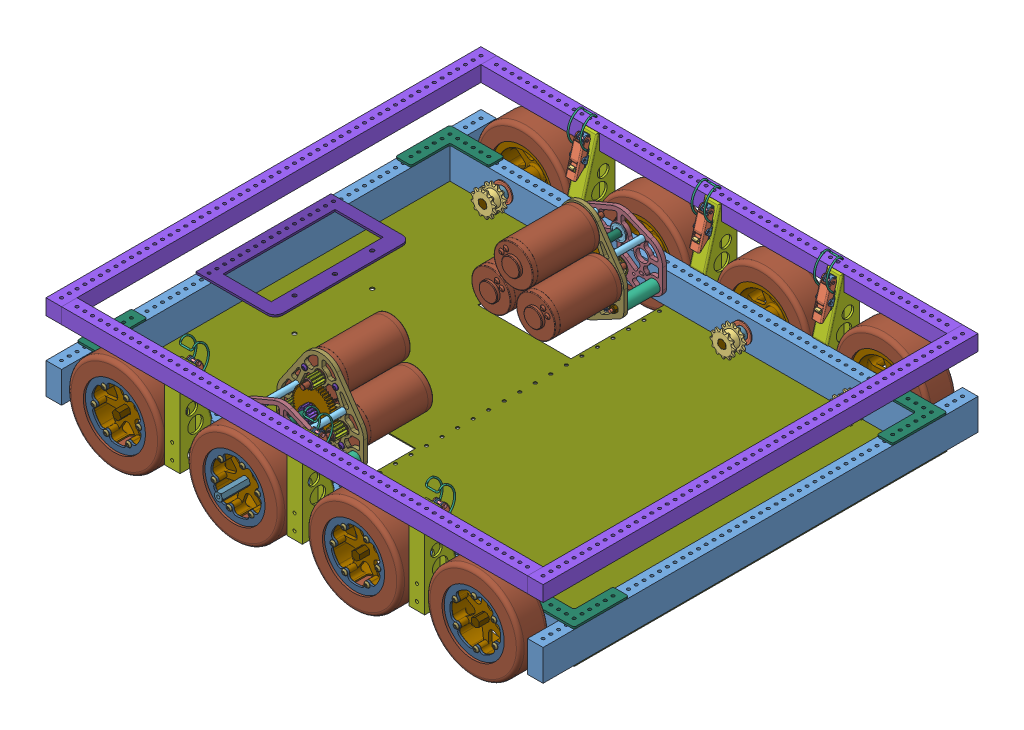
SolidWorks assembly 1991-17-DA-005, configuration Default. Lengths in mm.
Overall size (1080.45 259.05 1407.35).
273 component instances, 48 part files, 21 mates.
Components (placement in the parent):
- 1991-17-DA-001-1: 1991-17-DA-001 [Default] at (406.6265 809.065 1092.1988) size (1080.45 199.26 1407.35)
  - Master Frame Drivetrain-1: Master Frame Drivetrain [Default] at (262.4677 448.4138 629.0158) size (812.8 50.8 711.2)
  - 1991-17-DP-005-1: 1991-17-DP-005 [Default] at (-30.8765 451.5888 927.4658) x (-0.365997 0.930616 0) z (0.930616 0.365997 0) size (31.12 7.94 31.12)
  - 1991-17-DP-005-2: 1991-17-DP-005 [Default] at (164.6777 448.4138 927.4658) x (1 0 0) z (0 -1 0) size (31.12 7.94 31.12)
  - 1991-17-DP-005-3: 1991-17-DP-005 [Default] at (555.8119 451.5888 927.4658) x (0.865913 0.500195 0) z (0.500195 -0.865913 0) size (31.12 7.94 31.12)
  - 1991-17-DP-005-4: 1991-17-DP-005 [Default] at (360.2577 448.4138 927.4658) x (0.906341 -0.422547 0) z (-0.422547 -0.906341 0) size (31.12 7.94 31.12)
  - 1991-17-DP-005-5: 1991-17-DP-005 [Default] at (-30.8765 451.5888 914.7658) x (1 0 0) z (0 1 0) size (31.12 7.94 31.12)
  - 1991-17-DP-005-7: 1991-17-DP-005 [Default] at (360.2577 448.4138 914.7658) x (1 0 0) z (0 1 0) size (31.12 7.94 31.12)
  - 1991-17-DP-005-8: 1991-17-DP-005 [Default] at (555.8119 451.5888 914.7658) x (1 0 0) z (0 1 0) size (31.12 7.94 31.12)
  - 1991-17-DP-005-9: 1991-17-DP-005 [Default] at (555.8119 451.5888 343.2658) x (1 0 0) z (0 -1 0) size (31.12 7.94 31.12)
  - 1991-17-DP-005-10: 1991-17-DP-005 [Default] at (555.8119 451.5888 330.5658) x (1 0 0) z (0 1 0) size (31.12 7.94 31.12)
  - 1991-17-DP-005-11: 1991-17-DP-005 [Default] at (360.2577 448.4138 330.5658) x (1 0 0) z (0 1 0) size (31.12 7.94 31.12)
  - 1991-17-DP-005-12: 1991-17-DP-005 [Default] at (360.2577 448.4138 343.2658) x (1 0 0) z (0 -1 0) size (31.12 7.94 31.12)
  - 1991-17-DP-005-13: 1991-17-DP-005 [Default] at (164.6777 448.4138 343.2658) x (1 0 0) z (0 -1 0) size (31.12 7.94 31.12)
  - 1991-17-DP-005-15: 1991-17-DP-005 [Default] at (-30.8765 451.5888 330.5658) x (1 0 0) z (0 1 0) size (31.12 7.94 31.12)
  - 1991-17-DP-005-16: 1991-17-DP-005 [Default] at (-30.8765 451.5888 343.2658) x (1 0 0) z (0 -1 0) size (31.12 7.94 31.12)
  - 1991-17-DP-006-1: 1991-17-DP-006 [Default] at (-30.8765 451.5888 876.45) x (0.66365 -0.748043 0) z (0 0 1) size (40.29 40.29 21.35)
  - 1991-17-DP-006-2: 1991-17-DP-006 [Default] at (360.2577 448.4138 876.45) size (40.29 40.29 21.35)
  - 1991-17-DP-006-3: 1991-17-DP-006 [Default] at (555.8119 451.5888 876.45) size (40.29 40.29 21.35)
  - 1991-17-DP-006-4: 1991-17-DP-006 [Default] at (555.8119 451.5888 364.5255) x (0.485442 0.874269 0) z (0 0 1) size (40.29 40.29 21.35)
  - 1991-17-DP-006-5: 1991-17-DP-006 [Default] at (360.2577 448.4138 364.5255) x (0.316887 -0.948463 0) z (0 0 1) size (40.29 40.29 21.35)
  - 1991-17-DP-006-6: 1991-17-DP-006 [Default] at (-30.8765 451.5888 364.5255) size (40.29 40.29 21.35)
  - 1991-17-DA-002-1: 1991-17-DA-002 [Default] at (164.6777 495.4546 838.5658) size (142.06 172.49 287.64)
    - 217-2731-1: 217-2731 [Default] at (0 -47.0408 0) x (0.751182 -0.660095 0) z (-0.660095 -0.751182 0) size (31.12 7.94 31.12)
    - 217-2733-1: 217-2733 [Default] at (0 0 7.9375) x (0 0 -1) z (0.979051 -0.203616 0) size (7.11 24.61 24.61)
    - 217-2733-2: 217-2733 [Default] at (0 0 61.9125) x (0 0 1) z (-0.773016 -0.634387 0) size (7.11 24.61 24.61)
    - 217-2734-1: 217-2734 [Default] at (0 -47.0408 90.4875) x (1 0 0) z (0 -1 0) size (31.12 7.94 31.12)
    - 217-3099-001_12t-1: 217-3099-001_12t [Default] at (-36.6388 -14.5464 15.811) x (0.998588 0.053124 0) z (0 0 1) size (18.01 18.01 19.05)
    - 217-3099-001_12t-2: 217-3099-001_12t [Default] at (36.6388 -14.5464 15.811) x (0.998588 -0.053124 0) z (0 0 1) size (18.01 18.01 19.05)
    - 217-3099-001_12t-3: 217-3099-001_12t [Default] at (-0.0318 39.4208 15.811) x (-0.050001 -0.998749 0) z (0 0 1) size (18.01 18.01 19.05)
    - 217-3100-001_14t-1: 217-3100-001_14t [Default] at (0 0 26.9367) x (0.913978 0.405765 0) z (0 0 1) size (20.32 20.6 12.7)
    - 217-2711-002 Rev1_50t-1: 217-2711-002 Rev1_50t [Default] at (0 0 14.2621) x (-0.21459 -0.976704 0) z (0 0 1) size (66.7 66.76 12.65)
    - 217-2714-002 Rev1_60t-1: 217-2714-002 Rev1_60t [Default] at (0 -47.0408 26.9621) x (0.920953 -0.389675 0) z (0 0 1) size (78.95 78.95 12.65)
    - 217-2000-1: 217-2000 [Default] at (-36.6388 -14.5464 0) x (0 0 -1) z (0.998588 0.053124 0) size (150.2 64.01 64.01)
    - 217-2000-2: 217-2000 [Default] at (-0.0318 39.4208 0) x (0 0 -1) z (-0.050001 -0.998749 0) size (150.2 64.01 64.01)
    - 217-2000-3: 217-2000 [Default] at (36.6388 -14.5464 0) x (0 0 -1) z (0.998588 -0.053124 0) size (150.2 64.01 64.01)
    - 217-3421-001 Rev1-1: 217-3421-001 Rev1 [Default] at origin size (142.02 161.39 6.35)
    - 217-3421-002 Rev1-1: 217-3421-002 Rev1 [Default] at (0 0 69.85) x (-1 0 0) z (0 0 -1) size (142.06 121.97 6.35)
    - 217-3421-004 Rev1-1: 217-3421-004 Rev1 [Default] at (0 -47.0408 90.4875) x (-0.41446 0.910068 0) z (0 0 1) size (15.59 12.7 175.64)
    - 217-3422-001 Rev1-1: 217-3422-001 Rev1 [Default] at (0 0 34.925) x (0.99441 -0.105586 0) z (0 0 1) size (11.11 11.11 68.26)
    - 217-3422-004 Rev2-1: 217-3422-004 Rev2 [Default] at (0 -47.0408 96.8375) size (72.39 47.62 34.67)
    - 217-3421-009 Rev1-1: 217-3421-009 Rev1 [Default] at (35.2895 -39.9105 6.35) x (0 0 -1) z (-0.521716 -0.853119 0) size (15.78 9.26 9.25)
    - 217-3421-009 Rev1-2: 217-3421-009 Rev1 [Default] at (-25.4 40.6908 6.35) x (0 0 -1) z (-0.521716 -0.853119 0) size (15.78 9.26 9.25)
    - 217-3421-009 Rev1-3: 217-3421-009 Rev1 [Default] at (25.3365 38.1508 6.35) x (0 0 -1) z (-0.521716 -0.853119 0) size (15.78 9.26 9.25)
    - 217-3421-009 Rev1-4: 217-3421-009 Rev1 [Default] at (-35.2895 -39.9105 6.35) x (0 0 -1) z (-0.521716 -0.853119 0) size (15.78 9.26 9.25)
    - 217-3421-010 Rev1-1: 217-3421-010 Rev1 [Default] at (57.15 -47.0408 0) x (0.608161 -0.793814 0) z (0.793814 0.608161 0) size (9.53 6.13 11)
    - 217-3421-010 Rev1-2: 217-3421-010 Rev1 [Default] at (-57.15 -47.0408 0) x (0.608161 -0.793814 0) z (0.793814 0.608161 0) size (9.53 6.13 11)
    - 217-3421-011 Rev2_97633A200-1: 217-3421-011 Rev2_97633A200 [Default] at (0 -47.0408 -0.4445) x (0 0 -1) z (0.969555 0.244872 0) size (0.89 16.1 14.34)
    - 217-3422-005 Rev1-1: 217-3422-005 Rev1 [Default] at (57.15 -47.0408 73.025) x (0 0 -1) z (-0.704441 0.709763 0) size (87.6 7.92 7.92)
    - 217-3422-005 Rev1-2: 217-3422-005 Rev1 [Default] at (-57.15 -47.0408 73.025) x (0 0 -1) z (-0.704441 0.709763 0) size (87.6 7.92 7.92)
    - 217-3422-006 Rev1-1: 217-3422-006 Rev1 [Default] at (38.0118 10.8086 69.85) x (0 0 -1) z (-0.961271 0.275605 0) size (81.25 7.92 7.92)
    - 217-3422-006 Rev1-2: 217-3422-006 Rev1 [Default] at (-38.0118 10.8086 69.85) x (0 0 -1) z (-0.961271 0.275605 0) size (81.25 7.92 7.92)
    - 217-3422-007 Rev1-1: 217-3422-007 Rev1 [Default] at (23.8125 -47.0408 95.1993) x (0 0 1) z (-0.890461 -0.455059 0) size (35.11 10.21 10.21)
    - 217-3422-007 Rev1-2: 217-3422-007 Rev1 [Default] at (-23.8125 -47.0408 95.1993) x (0 0 1) z (-0.870387 -0.492369 0) size (35.11 10.21 10.21)
    - 217-3422-002 Rev1-1: 217-3422-002 Rev1 [Default] at (-37.9881 10.8177 34.925) size (9.53 9.53 57.15)
    - 217-3422-002 Rev1-2: 217-3422-002 Rev1 [Default] at (37.9881 10.8177 34.925) size (9.53 9.53 57.15)
    - 217-3422-003 Rev1-1: 217-3422-003 Rev1 [Default] at (-57.15 -47.0408 34.925) size (19.13 19.13 63.5)
    - 217-3422-003 Rev1-2: 217-3422-003 Rev1 [Default] at (57.15 -47.0408 34.925) x (0.853162 0.521647 0) z (0 0 1) size (19.13 19.13 63.5)
    - 217-3257-001 Rev1-1: 217-3257-001 Rev1 [Default] at (0 -47.0408 34.779) size (19.5 19.5 1.59)
    - 217-2758-001 Rev1-1: 217-2758-001 Rev1 [Default] at (0 -47.0408 55.4991) x (-0.35758 0.933882 0) z (0 0 1) size (19.05 19.05 3.17)
    - 217-3259-001 Rev1-1: 217-3259-001 Rev1 [Default] at (0 -47.0408 60.2616) x (-0.351317 0.936256 0) z (0 0 1) size (19.5 19.5 6.35)
    - 217-3261-001 Rev1-1: 217-3261-001 Rev1 [Default] at (0 -47.0408 14.2875) size (19.5 19.5 12.7)
    - 217-3263-001 Rev1-1: 217-3263-001 Rev1 [Default] at (0 -47.0408 77.7875) x (0.762918 -0.646495 0) z (0 0 1) size (19.5 19.5 25.4)
    - 217-2761-001 rev1-1: 217-2761-001 rev1 [Default] at (3.7635 39.2308 16.1) x (0.050001 0.998749 0) z (0 0 1) size (2 2 20)
    - 217-2761-001 rev1-2: 217-2761-001 rev1 [Default] at (-36.8407 -10.7518 16.1) x (0.998588 0.053124 0) z (0 0 1) size (2 2 20)
    - 217-2761-001 rev1-3: 217-2761-001 rev1 [Default] at (36.8407 -10.7518 16.1) x (0.998588 -0.053124 0) z (0 0 1) size (2 2 20)
    - 217-2614-002_98430A132-1: 217-2614-002_98430A132 [Default] at (-0.0318 39.4208 6.286) x (0 0 -1) z (0.996945 0.078111 0) size (1.2 14.83 14.83)
    - 217-2614-002_98430A132-2: 217-2614-002_98430A132 [Default] at (36.6388 -14.5464 6.286) x (0 0 -1) z (0.996945 0.078111 0) size (1.2 14.83 14.83)
    - 217-2614-002_98430A132-3: 217-2614-002_98430A132 [Default] at (-36.6388 -14.5464 6.286) x (0 0 -1) z (0.996945 0.078111 0) size (1.2 14.83 14.83)
    - 217-2614-002_98430A132-4: 217-2614-002_98430A132 [Default] at (-36.6388 -14.5464 26.4028) x (0 0 -1) z (0.996945 0.078111 0) size (1.2 14.83 14.83)
    - 217-2614-002_98430A132-5: 217-2614-002_98430A132 [Default] at (36.6388 -14.5464 26.4028) x (0 0 -1) z (0.996945 0.078111 0) size (1.2 14.83 14.83)
    - 217-2614-002_98430A132-6: 217-2614-002_98430A132 [Default] at (-0.0318 39.4208 26.4028) x (0 0 -1) z (0.996945 0.078111 0) size (1.2 14.83 14.83)
    - 217-3257-001 Rev1-2: 217-3257-001 Rev1 [Default] at (0 -47.0408 64.2938) size (19.5 19.5 1.59)
  - 1991-17-DA-002-2: 1991-17-DA-002 [Default] at (164.6777 495.4546 419.4658) x (-1 0 0) z (0 0 -1) size (142.06 172.49 287.64)
    - 217-2731-1: 217-2731 [Default] at (0 -47.0408 0) x (0.751182 -0.660095 0) z (-0.660095 -0.751182 0) size (31.12 7.94 31.12)
    - 217-2733-1: 217-2733 [Default] at (0 0 7.9375) x (0 0 -1) z (0.979051 -0.203616 0) size (7.11 24.61 24.61)
    - 217-2733-2: 217-2733 [Default] at (0 0 61.9125) x (0 0 1) z (-0.773016 -0.634387 0) size (7.11 24.61 24.61)
    - 217-2734-1: 217-2734 [Default] at (0 -47.0408 90.4875) x (1 0 0) z (0 -1 0) size (31.12 7.94 31.12)
    - 217-3099-001_12t-1: 217-3099-001_12t [Default] at (-36.6388 -14.5464 15.811) x (0.998588 0.053124 0) z (0 0 1) size (18.01 18.01 19.05)
    - 217-3099-001_12t-2: 217-3099-001_12t [Default] at (36.6388 -14.5464 15.811) x (0.998588 -0.053124 0) z (0 0 1) size (18.01 18.01 19.05)
    - 217-3099-001_12t-3: 217-3099-001_12t [Default] at (-0.0318 39.4208 15.811) x (-0.050001 -0.998749 0) z (0 0 1) size (18.01 18.01 19.05)
    - 217-3100-001_14t-1: 217-3100-001_14t [Default] at (0 0 26.9367) x (0.913978 0.405765 0) z (0 0 1) size (20.32 20.6 12.7)
    - 217-2711-002 Rev1_50t-1: 217-2711-002 Rev1_50t [Default] at (0 0 14.2621) x (-0.21459 -0.976704 0) z (0 0 1) size (66.7 66.76 12.65)
    - 217-2714-002 Rev1_60t-1: 217-2714-002 Rev1_60t [Default] at (0 -47.0408 26.9621) x (0.920953 -0.389675 0) z (0 0 1) size (78.95 78.95 12.65)
    - 217-2000-1: 217-2000 [Default] at (-36.6388 -14.5464 0) x (0 0 -1) z (0.998588 0.053124 0) size (150.2 64.01 64.01)
    - 217-2000-2: 217-2000 [Default] at (-0.0318 39.4208 0) x (0 0 -1) z (-0.050001 -0.998749 0) size (150.2 64.01 64.01)
    - 217-2000-3: 217-2000 [Default] at (36.6388 -14.5464 0) x (0 0 -1) z (0.998588 -0.053124 0) size (150.2 64.01 64.01)
    - 217-3421-001 Rev1-1: 217-3421-001 Rev1 [Default] at origin size (142.02 161.39 6.35)
    - 217-3421-002 Rev1-1: 217-3421-002 Rev1 [Default] at (0 0 69.85) x (-1 0 0) z (0 0 -1) size (142.06 121.97 6.35)
    - 217-3421-004 Rev1-1: 217-3421-004 Rev1 [Default] at (0 -47.0408 90.4875) x (-0.41446 0.910068 0) z (0 0 1) size (15.59 12.7 175.64)
    - 217-3422-001 Rev1-1: 217-3422-001 Rev1 [Default] at (0 0 34.925) x (0.99441 -0.105586 0) z (0 0 1) size (11.11 11.11 68.26)
    - 217-3422-004 Rev2-1: 217-3422-004 Rev2 [Default] at (0 -47.0408 96.8375) size (72.39 47.62 34.67)
    - 217-3421-009 Rev1-1: 217-3421-009 Rev1 [Default] at (35.2895 -39.9105 6.35) x (0 0 -1) z (-0.521716 -0.853119 0) size (15.78 9.26 9.25)
    - 217-3421-009 Rev1-2: 217-3421-009 Rev1 [Default] at (-25.4 40.6908 6.35) x (0 0 -1) z (-0.521716 -0.853119 0) size (15.78 9.26 9.25)
    - 217-3421-009 Rev1-3: 217-3421-009 Rev1 [Default] at (25.3365 38.1508 6.35) x (0 0 -1) z (-0.521716 -0.853119 0) size (15.78 9.26 9.25)
    - 217-3421-009 Rev1-4: 217-3421-009 Rev1 [Default] at (-35.2895 -39.9105 6.35) x (0 0 -1) z (-0.521716 -0.853119 0) size (15.78 9.26 9.25)
    - 217-3421-010 Rev1-1: 217-3421-010 Rev1 [Default] at (57.15 -47.0408 0) x (0.608161 -0.793814 0) z (0.793814 0.608161 0) size (9.53 6.13 11)
    - 217-3421-010 Rev1-2: 217-3421-010 Rev1 [Default] at (-57.15 -47.0408 0) x (0.608161 -0.793814 0) z (0.793814 0.608161 0) size (9.53 6.13 11)
    - 217-3421-011 Rev2_97633A200-1: 217-3421-011 Rev2_97633A200 [Default] at (0 -47.0408 -0.4445) x (0 0 -1) z (0.969555 0.244872 0) size (0.89 16.1 14.34)
    - 217-3422-005 Rev1-1: 217-3422-005 Rev1 [Default] at (57.15 -47.0408 73.025) x (0 0 -1) z (-0.704441 0.709763 0) size (87.6 7.92 7.92)
    - 217-3422-005 Rev1-2: 217-3422-005 Rev1 [Default] at (-57.15 -47.0408 73.025) x (0 0 -1) z (-0.704441 0.709763 0) size (87.6 7.92 7.92)
    - 217-3422-006 Rev1-1: 217-3422-006 Rev1 [Default] at (38.0118 10.8086 69.85) x (0 0 -1) z (-0.961271 0.275605 0) size (81.25 7.92 7.92)
    - 217-3422-006 Rev1-2: 217-3422-006 Rev1 [Default] at (-38.0118 10.8086 69.85) x (0 0 -1) z (-0.961271 0.275605 0) size (81.25 7.92 7.92)
    - 217-3422-007 Rev1-1: 217-3422-007 Rev1 [Default] at (23.8125 -47.0408 95.1993) x (0 0 1) z (-0.890461 -0.455059 0) size (35.11 10.21 10.21)
    - 217-3422-007 Rev1-2: 217-3422-007 Rev1 [Default] at (-23.8125 -47.0408 95.1993) x (0 0 1) z (-0.870387 -0.492369 0) size (35.11 10.21 10.21)
    - 217-3422-002 Rev1-1: 217-3422-002 Rev1 [Default] at (-37.9881 10.8177 34.925) size (9.53 9.53 57.15)
    - 217-3422-002 Rev1-2: 217-3422-002 Rev1 [Default] at (37.9881 10.8177 34.925) size (9.53 9.53 57.15)
    - 217-3422-003 Rev1-1: 217-3422-003 Rev1 [Default] at (-57.15 -47.0408 34.925) size (19.13 19.13 63.5)
    - 217-3422-003 Rev1-2: 217-3422-003 Rev1 [Default] at (57.15 -47.0408 34.925) x (0.853162 0.521647 0) z (0 0 1) size (19.13 19.13 63.5)
    - 217-3257-001 Rev1-1: 217-3257-001 Rev1 [Default] at (0 -47.0408 34.779) size (19.5 19.5 1.59)
    - 217-2758-001 Rev1-1: 217-2758-001 Rev1 [Default] at (0 -47.0408 55.4991) x (-0.35758 0.933882 0) z (0 0 1) size (19.05 19.05 3.17)
    - 217-3259-001 Rev1-1: 217-3259-001 Rev1 [Default] at (0 -47.0408 60.2616) x (-0.351317 0.936256 0) z (0 0 1) size (19.5 19.5 6.35)
    - 217-3261-001 Rev1-1: 217-3261-001 Rev1 [Default] at (0 -47.0408 14.2875) size (19.5 19.5 12.7)
    - 217-3263-001 Rev1-1: 217-3263-001 Rev1 [Default] at (0 -47.0408 77.7875) x (0.762918 -0.646495 0) z (0 0 1) size (19.5 19.5 25.4)
    - 217-2761-001 rev1-1: 217-2761-001 rev1 [Default] at (3.7635 39.2308 16.1) x (0.050001 0.998749 0) z (0 0 1) size (2 2 20)
    - 217-2761-001 rev1-2: 217-2761-001 rev1 [Default] at (-36.8407 -10.7518 16.1) x (0.998588 0.053124 0) z (0 0 1) size (2 2 20)
    - 217-2761-001 rev1-3: 217-2761-001 rev1 [Default] at (36.8407 -10.7518 16.1) x (0.998588 -0.053124 0) z (0 0 1) size (2 2 20)
    - 217-2614-002_98430A132-1: 217-2614-002_98430A132 [Default] at (-0.0318 39.4208 6.286) x (0 0 -1) z (0.996945 0.078111 0) size (1.2 14.83 14.83)
    - 217-2614-002_98430A132-2: 217-2614-002_98430A132 [Default] at (36.6388 -14.5464 6.286) x (0 0 -1) z (0.996945 0.078111 0) size (1.2 14.83 14.83)
    - 217-2614-002_98430A132-3: 217-2614-002_98430A132 [Default] at (-36.6388 -14.5464 6.286) x (0 0 -1) z (0.996945 0.078111 0) size (1.2 14.83 14.83)
    - 217-2614-002_98430A132-4: 217-2614-002_98430A132 [Default] at (-36.6388 -14.5464 26.4028) x (0 0 -1) z (0.996945 0.078111 0) size (1.2 14.83 14.83)
    - 217-2614-002_98430A132-5: 217-2614-002_98430A132 [Default] at (36.6388 -14.5464 26.4028) x (0 0 -1) z (0.996945 0.078111 0) size (1.2 14.83 14.83)
    - 217-2614-002_98430A132-6: 217-2614-002_98430A132 [Default] at (-0.0318 39.4208 26.4028) x (0 0 -1) z (0.996945 0.078111 0) size (1.2 14.83 14.83)
    - 217-3257-001 Rev1-2: 217-3257-001 Rev1 [Default] at (0 -47.0408 64.2938) size (19.5 19.5 1.59)
  - 1991-17-DP-006-7: 1991-17-DP-006 [Default] at (164.6777 448.4138 876.45) size (40.29 40.29 21.35)
  - 1991-17-DP-006-8: 1991-17-DP-006 [Default] at (164.6777 448.4138 364.5255) size (40.29 40.29 21.35)
  - 1991-17-DP-007-1: 1991-17-DP-007 [Default] at (360.2577 448.4138 351.2032) x (0.999949 -0.01009 0) z (0 0 1) size (19.05 19.05 11.18)
  - 1991-17-DP-007-2: 1991-17-DP-007 [Default] at (555.8119 451.5888 351.2033) x (0.991459 -0.130416 0) z (0 0 1) size (19.05 19.05 11.18)
  - 1991-17-DP-007-3: 1991-17-DP-007 [Default] at (555.8119 451.5888 895.6523) x (0.999479 -0.032269 0) z (0 0 1) size (19.05 19.05 11.18)
  - 1991-17-DP-007-4: 1991-17-DP-007 [Default] at (360.2577 448.4138 895.6523) x (0.999398 0.034699 0) z (0 0 1) size (19.05 19.05 11.18)
  - 1991-17-DP-007-5: 1991-17-DP-007 [Default] at (-30.8765 451.5888 895.6524) x (0.918059 -0.396445 0) z (0 0 1) size (19.05 19.05 11.18)
  - 1991-17-DP-007-6: 1991-17-DP-007 [Default] at (-30.8765 451.5888 351.2032) size (19.05 19.05 11.18)
  - 1991-17-DP-009-1: 1991-17-DP-009 [Default] at (668.8677 473.8138 844.9158) x (-1 0 0) z (0 0 -1) size (88.9 3.17 88.9)
  - 1991-17-DP-009-2: 1991-17-DP-009 [Default] at (579.9677 473.8138 324.2158) x (0 0 1) z (-1 0 0) size (88.9 3.17 88.9)
  - 1991-17-DP-009-3: 1991-17-DP-009 [Default] at (-143.9323 473.8138 413.1158) size (88.9 3.17 88.9)
  - 1991-17-DP-009-4: 1991-17-DP-009 [Default] at (-55.0323 473.8138 933.8158) x (0 0 -1) z (1 0 0) size (88.9 3.17 88.9)
  - 1991-17-DP-010-1: 1991-17-DP-010 [Default] at (-143.9323 421.4263 324.2158) x (0 0 1) z (-1 0 0) size (609.6 1.59 812.8)
  - 1991-17-DP-011-1: 1991-17-DP-011 [Default] at (-79.1623 473.8138 629.0158) x (0 0 1) z (-1 0 0) size (220.98 3.17 129.54)
  - 1991-17-DP-012-1: 1991-17-DP-012 [Default] at (-30.8807 451.5996 329.7529) x (-0.365997 0.930616 0) z (0 0 1) size (14.66 12.7 107.95)
  - 1991-17-DP-012-2: 1991-17-DP-012 [Default] at (360.2672 448.4205 329.7529) x (0.087234 -0.996188 0) z (0 0 1) size (14.66 12.7 107.95)
  - 1991-17-DP-012-3: 1991-17-DP-012 [Default] at (555.8019 451.5946 329.7529) x (0.865913 0.500195 0) z (0 0 1) size (14.66 12.7 107.95)
  - 1991-17-DP-012-4: 1991-17-DP-012 [Default] at (555.8019 451.5946 928.2787) x (0.865913 0.500195 0) z (0 0 1) size (14.66 12.7 107.95)
  - 1991-17-DP-012-5: 1991-17-DP-012 [Default] at (360.2672 448.4205 928.2787) x (0.087234 -0.996188 0) z (0 0 1) size (14.66 12.7 107.95)
  - 1991-17-DP-012-6: 1991-17-DP-012 [Default] at (-30.8807 451.5996 928.2787) x (-0.365997 0.930616 0) z (0 0 1) size (14.66 12.7 107.95)
  - 1991-17-DA-003-1: 1991-17-DA-003 [Default] at (462.8327 537.6125 948.7419) x (1 0 0) z (0 0.961524 0.274721) size (23.75 31.36 88.93)
    - 1256B-1: 1256B [Default] at origin size (21.85 11.11 42.86)
    - 1256A-1: 1256A [Default] at (0 7.786 -8.5531) size (16.4 11.75 57.3)
    - 1256E-1: 1256E [Default] at (0 2.1 5.2687) size (17.5 15.13 27.5)
    - 569-2-1: 569-2 [Default] at (0.2 7.62 16.6687) size (18.02 5.86 5.81)
    - RIVET-2-1: RIVET-2 [Default] at (0 0 -8.2313) size (4.23 2.64 4.27)
    - 645C-1: 645C [Default] at (0 6.3871 15.3627) x (-1 0 0) z (0 -0.098785 -0.995109) size (23.75 26.55 49.93)
  - 1991-17-DA-003-2: 1991-17-DA-003 [Default] at (262.8077 537.6125 948.7419) x (1 0 0) z (0 0.961524 0.274721) size (23.75 31.36 88.93)
    - 1256B-1: 1256B [Default] at origin size (21.85 11.11 42.86)
    - 1256A-1: 1256A [Default] at (0 7.786 -8.5531) size (16.4 11.75 57.3)
    - 1256E-1: 1256E [Default] at (0 2.1 5.2687) size (17.5 15.13 27.5)
    - 569-2-1: 569-2 [Default] at (0.2 7.62 16.6687) size (18.02 5.86 5.81)
    - RIVET-2-1: RIVET-2 [Default] at (0 0 -8.2313) size (4.23 2.64 4.27)
    - 645C-1: 645C [Default] at (0 6.3871 15.3627) x (-1 0 0) z (0 -0.098785 -0.995109) size (23.75 26.55 49.93)
  - 1991-17-DA-003-3: 1991-17-DA-003 [Default] at (60.2427 537.6125 948.7419) x (1 0 0) z (0 0.961524 0.274721) size (23.75 31.36 88.93)
    - 1256B-1: 1256B [Default] at origin size (21.85 11.11 42.86)
    - 1256A-1: 1256A [Default] at (0 7.786 -8.5531) size (16.4 11.75 57.3)
    - 1256E-1: 1256E [Default] at (0 2.1 5.2687) size (17.5 15.13 27.5)
    - 569-2-1: 569-2 [Default] at (0.2 7.62 16.6687) size (18.02 5.86 5.81)
    - RIVET-2-1: RIVET-2 [Default] at (0 0 -8.2313) size (4.23 2.64 4.27)
    - 645C-1: 645C [Default] at (0 6.3871 15.3627) x (-1 0 0) z (0 -0.098785 -0.995109) size (23.75 26.55 49.93)
  - 1991-17-DA-003-4: 1991-17-DA-003 [Default] at (462.8327 536.9449 309.2975) x (-1 0 0) z (0 0.961524 -0.274721) size (23.75 31.36 88.93)
    - 1256B-1: 1256B [Default] at origin size (21.85 11.11 42.86)
    - 1256A-1: 1256A [Default] at (0 7.786 -8.5531) size (16.4 11.75 57.3)
    - 1256E-1: 1256E [Default] at (0 2.1 5.2687) size (17.5 15.13 27.5)
    - 569-2-1: 569-2 [Default] at (0.2 7.62 16.6687) size (18.02 5.86 5.81)
    - RIVET-2-1: RIVET-2 [Default] at (0 0 -8.2313) size (4.23 2.64 4.27)
    - 645C-1: 645C [Default] at (0 6.3871 15.3627) x (-1 0 0) z (0 -0.098785 -0.995109) size (23.75 26.55 49.93)
  - 1991-17-DA-003-5: 1991-17-DA-003 [Default] at (262.8077 536.9932 309.4665) x (-1 0 0) z (0 0.961524 -0.274721) size (23.75 31.36 88.93)
    - 1256B-1: 1256B [Default] at origin size (21.85 11.11 42.86)
    - 1256A-1: 1256A [Default] at (0 7.786 -8.5531) size (16.4 11.75 57.3)
    - 1256E-1: 1256E [Default] at (0 2.1 5.2687) size (17.5 15.13 27.5)
    - 569-2-1: 569-2 [Default] at (0.2 7.62 16.6687) size (18.02 5.86 5.81)
    - RIVET-2-1: RIVET-2 [Default] at (0 0 -8.2313) size (4.23 2.64 4.27)
    - 645C-1: 645C [Default] at (0 6.3871 15.3627) x (-1 0 0) z (0 -0.098785 -0.995109) size (23.75 26.55 49.93)
  - 1991-17-DA-003-6: 1991-17-DA-003 [Default] at (60.2427 536.9932 309.4665) x (-1 0 0) z (0 0.961524 -0.274721) size (23.75 31.36 88.93)
    - 1256B-1: 1256B [Default] at origin size (21.85 11.11 42.86)
    - 1256A-1: 1256A [Default] at (0 7.786 -8.5531) size (16.4 11.75 57.3)
    - 1256E-1: 1256E [Default] at (0 2.1 5.2687) size (17.5 15.13 27.5)
    - 569-2-1: 569-2 [Default] at (0.2 7.62 16.6687) size (18.02 5.86 5.81)
    - RIVET-2-1: RIVET-2 [Default] at (0 0 -8.2313) size (4.23 2.64 4.27)
    - 645C-1: 645C [Default] at (0 6.3871 15.3627) x (-1 0 0) z (0 -0.098785 -0.995109) size (23.75 26.55 49.93)
  - 1991-17-DP-019-1: 1991-17-DP-019 [Default] at (462.4927 423.0138 298.8158) x (0 0 1) z (-1 0 0) size (53.25 139.97 25.4)
  - 1991-17-DP-019-2: 1991-17-DP-019 [Default] at (262.4677 423.0138 298.8158) x (0 0 1) z (-1 0 0) size (53.25 139.97 25.4)
  - 1991-17-DP-019-3: 1991-17-DP-019 [Default] at (62.4427 423.0138 298.8158) x (0 0 1) z (-1 0 0) size (53.25 139.97 25.4)
  - 1991-17-DP-019-4: 1991-17-DP-019 [Default] at (462.4927 423.0138 959.2158) x (0 0 -1) z (1 0 0) size (53.25 139.97 25.4)
  - 1991-17-DP-019-5: 1991-17-DP-019 [Default] at (262.4677 423.0138 959.2158) x (0 0 -1) z (1 0 0) size (53.25 139.97 25.4)
  - 1991-17-DP-019-6: 1991-17-DP-019 [Default] at (62.4427 423.0138 959.2158) x (0 0 -1) z (1 0 0) size (53.25 139.97 25.4)
  - 1991-17-DP-014-2: 1991-17-DP-014 [Default] at (-118.5323 550.0138 273.4158) x (0 0 1) z (-1 0 0) size (711.2 25.4 812.8)
- 1991-17-DA-004-1: 1991-17-DA-004 [Default] at (375.7726 1260.5964 1392.9196) x (0.365997 -0.930616 0) z (0 0 1) size (196.26 196.26 50.48)
  - WCP-0049-001 Rev1-1: WCP-0049-001 Rev1 [Default] at origin size (101.6 101.6 43.82)
  - WCP-0049-002 Rev1-1: WCP-0049-002 Rev1 [Default] at (0 0 -23.495) size (101.6 101.6 3.17)
  - WCP-0047-001 Rev1-1: WCP-0047-001 Rev1 [Default] at (0 0 -4.7625) x (0.330828 0.943691 0) z (0 0 1) size (153.99 153.99 47.63)
  - mcmaster_91255A265_91255A265-1: mcmaster_91255A265_91255A265 [Default] at (31.7509 18.3314 -27.6479) x (-0.742658 0.66967 0) z (0 0 -1) size (9.24 9.28 15.86)
  - mcmaster_91255A265_91255A265-2: mcmaster_91255A265_91255A265 [Default] at (31.7509 -18.3314 -27.6479) x (0.208622 0.977996 0) z (0 0 -1) size (9.24 9.28 15.86)
  - mcmaster_91255A265_91255A265-3: mcmaster_91255A265_91255A265 [Default] at (0 -36.6627 -27.6479) x (0.951281 0.308326 0) z (0 0 -1) size (9.24 9.28 15.86)
  - mcmaster_91255A265_91255A265-4: mcmaster_91255A265_91255A265 [Default] at (-31.7509 -18.3314 -27.6479) x (0.742658 -0.66967 0) z (0 0 -1) size (9.24 9.28 15.86)
  - mcmaster_91255A265_91255A265-5: mcmaster_91255A265_91255A265 [Default] at (-31.7509 18.3314 -27.6479) x (-0.208622 -0.977996 0) z (0 0 -1) size (9.24 9.28 15.86)
  - mcmaster_91255A265_91255A265-6: mcmaster_91255A265_91255A265 [Default] at (0 36.6627 -27.6479) x (-0.951281 -0.308326 0) z (0 0 -1) size (9.24 9.28 15.86)
- 1991-17-DA-004-2: 1991-17-DA-004 [Default] at (571.2616 1257.4192 1392.9196) x (0.41446 -0.910068 0) z (0 0 1) size (196.26 196.26 50.48)
  - WCP-0049-001 Rev1-1: WCP-0049-001 Rev1 [Default] at origin size (101.6 101.6 43.82)
  - WCP-0049-002 Rev1-1: WCP-0049-002 Rev1 [Default] at (0 0 -23.495) size (101.6 101.6 3.17)
  - WCP-0047-001 Rev1-1: WCP-0047-001 Rev1 [Default] at (0 0 -4.7625) x (0.330828 0.943691 0) z (0 0 1) size (153.99 153.99 47.63)
  - mcmaster_91255A265_91255A265-1: mcmaster_91255A265_91255A265 [Default] at (31.7509 18.3314 -27.6479) x (-0.742658 0.66967 0) z (0 0 -1) size (9.24 9.28 15.86)
  - mcmaster_91255A265_91255A265-2: mcmaster_91255A265_91255A265 [Default] at (31.7509 -18.3314 -27.6479) x (0.208622 0.977996 0) z (0 0 -1) size (9.24 9.28 15.86)
  - mcmaster_91255A265_91255A265-3: mcmaster_91255A265_91255A265 [Default] at (0 -36.6627 -27.6479) x (0.951281 0.308326 0) z (0 0 -1) size (9.24 9.28 15.86)
  - mcmaster_91255A265_91255A265-4: mcmaster_91255A265_91255A265 [Default] at (-31.7509 -18.3314 -27.6479) x (0.742658 -0.66967 0) z (0 0 -1) size (9.24 9.28 15.86)
  - mcmaster_91255A265_91255A265-5: mcmaster_91255A265_91255A265 [Default] at (-31.7509 18.3314 -27.6479) x (-0.208622 -0.977996 0) z (0 0 -1) size (9.24 9.28 15.86)
  - mcmaster_91255A265_91255A265-6: mcmaster_91255A265_91255A265 [Default] at (0 36.6627 -27.6479) x (-0.951281 -0.308326 0) z (0 0 -1) size (9.24 9.28 15.86)
- 1991-17-DA-004-3: 1991-17-DA-004 [Default] at (766.8336 1257.4435 1392.9196) x (-0.819107 -0.573641 0) z (0 0 1) size (196.26 196.26 50.48)
  - WCP-0049-001 Rev1-1: WCP-0049-001 Rev1 [Default] at origin size (101.6 101.6 43.82)
  - WCP-0049-002 Rev1-1: WCP-0049-002 Rev1 [Default] at (0 0 -23.495) size (101.6 101.6 3.17)
  - WCP-0047-001 Rev1-1: WCP-0047-001 Rev1 [Default] at (0 0 -4.7625) x (0.330828 0.943691 0) z (0 0 1) size (153.99 153.99 47.63)
  - mcmaster_91255A265_91255A265-1: mcmaster_91255A265_91255A265 [Default] at (31.7509 18.3314 -27.6479) x (-0.742658 0.66967 0) z (0 0 -1) size (9.24 9.28 15.86)
  - mcmaster_91255A265_91255A265-2: mcmaster_91255A265_91255A265 [Default] at (31.7509 -18.3314 -27.6479) x (0.208622 0.977996 0) z (0 0 -1) size (9.24 9.28 15.86)
  - mcmaster_91255A265_91255A265-3: mcmaster_91255A265_91255A265 [Default] at (0 -36.6627 -27.6479) x (0.951281 0.308326 0) z (0 0 -1) size (9.24 9.28 15.86)
  - mcmaster_91255A265_91255A265-4: mcmaster_91255A265_91255A265 [Default] at (-31.7509 -18.3314 -27.6479) x (0.742658 -0.66967 0) z (0 0 -1) size (9.24 9.28 15.86)
  - mcmaster_91255A265_91255A265-5: mcmaster_91255A265_91255A265 [Default] at (-31.7509 18.3314 -27.6479) x (-0.208622 -0.977996 0) z (0 0 -1) size (9.24 9.28 15.86)
  - mcmaster_91255A265_91255A265-6: mcmaster_91255A265_91255A265 [Default] at (0 36.6627 -27.6479) x (-0.951281 -0.308326 0) z (0 0 -1) size (9.24 9.28 15.86)
- 1991-17-DA-004-4: 1991-17-DA-004 [Default] at (962.4284 1260.5863 1392.9196) x (0.000225 -1 0) z (0 0 1) size (196.26 196.26 50.48)
  - WCP-0049-001 Rev1-1: WCP-0049-001 Rev1 [Default] at origin size (101.6 101.6 43.82)
  - WCP-0049-002 Rev1-1: WCP-0049-002 Rev1 [Default] at (0 0 -23.495) size (101.6 101.6 3.17)
  - WCP-0047-001 Rev1-1: WCP-0047-001 Rev1 [Default] at (0 0 -4.7625) x (0.330828 0.943691 0) z (0 0 1) size (153.99 153.99 47.63)
  - mcmaster_91255A265_91255A265-1: mcmaster_91255A265_91255A265 [Default] at (31.7509 18.3314 -27.6479) x (-0.742658 0.66967 0) z (0 0 -1) size (9.24 9.28 15.86)
  - mcmaster_91255A265_91255A265-2: mcmaster_91255A265_91255A265 [Default] at (31.7509 -18.3314 -27.6479) x (0.208622 0.977996 0) z (0 0 -1) size (9.24 9.28 15.86)
  - mcmaster_91255A265_91255A265-3: mcmaster_91255A265_91255A265 [Default] at (0 -36.6627 -27.6479) x (0.951281 0.308326 0) z (0 0 -1) size (9.24 9.28 15.86)
  - mcmaster_91255A265_91255A265-4: mcmaster_91255A265_91255A265 [Default] at (-31.7509 -18.3314 -27.6479) x (0.742658 -0.66967 0) z (0 0 -1) size (9.24 9.28 15.86)
  - mcmaster_91255A265_91255A265-5: mcmaster_91255A265_91255A265 [Default] at (-31.7509 18.3314 -27.6479) x (-0.208622 -0.977996 0) z (0 0 -1) size (9.24 9.28 15.86)
  - mcmaster_91255A265_91255A265-6: mcmaster_91255A265_91255A265 [Default] at (0 36.6627 -27.6479) x (-0.951281 -0.308326 0) z (0 0 -1) size (9.24 9.28 15.86)
- 1991-17-DA-004-5: 1991-17-DA-004 [Default] at (962.4284 1260.5863 2049.5096) x (-0.998884 -0.047226 0) z (0 0 -1) size (196.26 196.26 50.48)
  - WCP-0049-001 Rev1-1: WCP-0049-001 Rev1 [Default] at origin size (101.6 101.6 43.82)
  - WCP-0049-002 Rev1-1: WCP-0049-002 Rev1 [Default] at (0 0 -23.495) size (101.6 101.6 3.17)
  - WCP-0047-001 Rev1-1: WCP-0047-001 Rev1 [Default] at (0 0 -4.7625) x (0.330828 0.943691 0) z (0 0 1) size (153.99 153.99 47.63)
  - mcmaster_91255A265_91255A265-1: mcmaster_91255A265_91255A265 [Default] at (31.7509 18.3314 -27.6479) x (-0.742658 0.66967 0) z (0 0 -1) size (9.24 9.28 15.86)
  - mcmaster_91255A265_91255A265-2: mcmaster_91255A265_91255A265 [Default] at (31.7509 -18.3314 -27.6479) x (0.208622 0.977996 0) z (0 0 -1) size (9.24 9.28 15.86)
  - mcmaster_91255A265_91255A265-3: mcmaster_91255A265_91255A265 [Default] at (0 -36.6627 -27.6479) x (0.951281 0.308326 0) z (0 0 -1) size (9.24 9.28 15.86)
  - mcmaster_91255A265_91255A265-4: mcmaster_91255A265_91255A265 [Default] at (-31.7509 -18.3314 -27.6479) x (0.742658 -0.66967 0) z (0 0 -1) size (9.24 9.28 15.86)
  - mcmaster_91255A265_91255A265-5: mcmaster_91255A265_91255A265 [Default] at (-31.7509 18.3314 -27.6479) x (-0.208622 -0.977996 0) z (0 0 -1) size (9.24 9.28 15.86)
  - mcmaster_91255A265_91255A265-6: mcmaster_91255A265_91255A265 [Default] at (0 36.6627 -27.6479) x (-0.951281 -0.308326 0) z (0 0 -1) size (9.24 9.28 15.86)
- 1991-17-DA-004-6: 1991-17-DA-004 [Default] at (766.8336 1257.4435 2049.5096) x (0.855997 0.516981 0) z (0 0 -1) size (196.26 196.26 50.48)
  - WCP-0049-001 Rev1-1: WCP-0049-001 Rev1 [Default] at origin size (101.6 101.6 43.82)
  - WCP-0049-002 Rev1-1: WCP-0049-002 Rev1 [Default] at (0 0 -23.495) size (101.6 101.6 3.17)
  - WCP-0047-001 Rev1-1: WCP-0047-001 Rev1 [Default] at (0 0 -4.7625) x (0.330828 0.943691 0) z (0 0 1) size (153.99 153.99 47.63)
  - mcmaster_91255A265_91255A265-1: mcmaster_91255A265_91255A265 [Default] at (31.7509 18.3314 -27.6479) x (-0.742658 0.66967 0) z (0 0 -1) size (9.24 9.28 15.86)
  - mcmaster_91255A265_91255A265-2: mcmaster_91255A265_91255A265 [Default] at (31.7509 -18.3314 -27.6479) x (0.208622 0.977996 0) z (0 0 -1) size (9.24 9.28 15.86)
  - mcmaster_91255A265_91255A265-3: mcmaster_91255A265_91255A265 [Default] at (0 -36.6627 -27.6479) x (0.951281 0.308326 0) z (0 0 -1) size (9.24 9.28 15.86)
  - mcmaster_91255A265_91255A265-4: mcmaster_91255A265_91255A265 [Default] at (-31.7509 -18.3314 -27.6479) x (0.742658 -0.66967 0) z (0 0 -1) size (9.24 9.28 15.86)
  - mcmaster_91255A265_91255A265-5: mcmaster_91255A265_91255A265 [Default] at (-31.7509 18.3314 -27.6479) x (-0.208622 -0.977996 0) z (0 0 -1) size (9.24 9.28 15.86)
  - mcmaster_91255A265_91255A265-6: mcmaster_91255A265_91255A265 [Default] at (0 36.6627 -27.6479) x (-0.951281 -0.308326 0) z (0 0 -1) size (9.24 9.28 15.86)
- 1991-17-DA-004-7: 1991-17-DA-004 [Default] at (571.2616 1257.4192 2049.5096) x (0.732856 0.680383 0) z (0 0 -1) size (196.26 196.26 50.48)
  - WCP-0049-001 Rev1-1: WCP-0049-001 Rev1 [Default] at origin size (101.6 101.6 43.82)
  - WCP-0049-002 Rev1-1: WCP-0049-002 Rev1 [Default] at (0 0 -23.495) size (101.6 101.6 3.17)
  - WCP-0047-001 Rev1-1: WCP-0047-001 Rev1 [Default] at (0 0 -4.7625) x (0.330828 0.943691 0) z (0 0 1) size (153.99 153.99 47.63)
  - mcmaster_91255A265_91255A265-1: mcmaster_91255A265_91255A265 [Default] at (31.7509 18.3314 -27.6479) x (-0.742658 0.66967 0) z (0 0 -1) size (9.24 9.28 15.86)
  - mcmaster_91255A265_91255A265-2: mcmaster_91255A265_91255A265 [Default] at (31.7509 -18.3314 -27.6479) x (0.208622 0.977996 0) z (0 0 -1) size (9.24 9.28 15.86)
  - mcmaster_91255A265_91255A265-3: mcmaster_91255A265_91255A265 [Default] at (0 -36.6627 -27.6479) x (0.951281 0.308326 0) z (0 0 -1) size (9.24 9.28 15.86)
  - mcmaster_91255A265_91255A265-4: mcmaster_91255A265_91255A265 [Default] at (-31.7509 -18.3314 -27.6479) x (0.742658 -0.66967 0) z (0 0 -1) size (9.24 9.28 15.86)
  - mcmaster_91255A265_91255A265-5: mcmaster_91255A265_91255A265 [Default] at (-31.7509 18.3314 -27.6479) x (-0.208622 -0.977996 0) z (0 0 -1) size (9.24 9.28 15.86)
  - mcmaster_91255A265_91255A265-6: mcmaster_91255A265_91255A265 [Default] at (0 36.6627 -27.6479) x (-0.951281 -0.308326 0) z (0 0 -1) size (9.24 9.28 15.86)
- 1991-17-DA-004-8: 1991-17-DA-004 [Default] at (375.7726 1260.5964 2049.5096) x (0.834926 0.550362 0) z (0 0 -1) size (196.26 196.26 50.48)
  - WCP-0049-001 Rev1-1: WCP-0049-001 Rev1 [Default] at origin size (101.6 101.6 43.82)
  - WCP-0049-002 Rev1-1: WCP-0049-002 Rev1 [Default] at (0 0 -23.495) size (101.6 101.6 3.17)
  - WCP-0047-001 Rev1-1: WCP-0047-001 Rev1 [Default] at (0 0 -4.7625) x (0.330828 0.943691 0) z (0 0 1) size (153.99 153.99 47.63)
  - mcmaster_91255A265_91255A265-1: mcmaster_91255A265_91255A265 [Default] at (31.7509 18.3314 -27.6479) x (-0.742658 0.66967 0) z (0 0 -1) size (9.24 9.28 15.86)
  - mcmaster_91255A265_91255A265-2: mcmaster_91255A265_91255A265 [Default] at (31.7509 -18.3314 -27.6479) x (0.208622 0.977996 0) z (0 0 -1) size (9.24 9.28 15.86)
  - mcmaster_91255A265_91255A265-3: mcmaster_91255A265_91255A265 [Default] at (0 -36.6627 -27.6479) x (0.951281 0.308326 0) z (0 0 -1) size (9.24 9.28 15.86)
  - mcmaster_91255A265_91255A265-4: mcmaster_91255A265_91255A265 [Default] at (-31.7509 -18.3314 -27.6479) x (0.742658 -0.66967 0) z (0 0 -1) size (9.24 9.28 15.86)
  - mcmaster_91255A265_91255A265-5: mcmaster_91255A265_91255A265 [Default] at (-31.7509 18.3314 -27.6479) x (-0.208622 -0.977996 0) z (0 0 -1) size (9.24 9.28 15.86)
  - mcmaster_91255A265_91255A265-6: mcmaster_91255A265_91255A265 [Default] at (0 36.6627 -27.6479) x (-0.951281 -0.308326 0) z (0 0 -1) size (9.24 9.28 15.86)
Mates (geometry in assembly coordinates):
- Concentric1: concentric anti-aligned: cylinder of 1991-17-DA-004-1/WCP-0047-001 Rev1-1 through (375.7726 1260.5964 1371.0121) axis (0 0 -1) radius 76.9938; cylinder of 1991-17-DA-004-8/WCP-0047-001 Rev1-1 through (375.7726 1260.5964 2071.4171) axis (0 0 1) radius 76.9938
- Concentric2: concentric anti-aligned: cylinder of 1991-17-DA-004-2/WCP-0047-001 Rev1-1 through (571.2616 1257.4192 1371.0121) axis (0 0 -1) radius 76.9938; cylinder of 1991-17-DA-004-7/WCP-0047-001 Rev1-1 through (571.2616 1257.4192 2071.4171) axis (0 0 1) radius 76.9938
- Concentric3: concentric anti-aligned: cylinder of 1991-17-DA-004-3/WCP-0047-001 Rev1-1 through (766.8336 1257.4435 1371.0121) axis (0 0 -1) radius 76.9938; cylinder of 1991-17-DA-004-6/WCP-0047-001 Rev1-1 through (766.8336 1257.4435 2071.4171) axis (0 0 1) radius 76.9938
- Concentric4: concentric anti-aligned: cylinder of 1991-17-DA-004-4/WCP-0047-001 Rev1-1 through (962.4284 1260.5863 1371.0121) axis (0 0 -1) radius 76.9938; cylinder of 1991-17-DA-004-5/WCP-0047-001 Rev1-1 through (962.4284 1260.5863 2071.4171) axis (0 0 1) radius 76.9938
- Coincident1: coincident anti-aligned: plane of 1991-17-DA-001-1/1991-17-DP-012-6 through (373.0621 1267.4882 2074.4525) normal (-0.78227 0.622939 0); plane of 1991-17-DA-004-1/WCP-0049-001 Rev1-1 through (373.0621 1267.4882 1371.0121) normal (0.78227 -0.622939 0)
- Coincident2: coincident anti-aligned: plane of 1991-17-DA-001-1/1991-17-DP-012-6 through (380.3133 1266.4005 2074.4525) normal (0.148346 0.988936 0); plane of 1991-17-DA-004-1/WCP-0049-001 Rev1-1 through (380.3859 1266.3896 1371.0121) normal (-0.148346 -0.988936 0)
- Coincident3: coincident anti-aligned: plane of 1991-17-DA-001-1/1991-17-DA-002-1/217-3421-004 Rev1-1 through (575.5636 1263.4472 2103.8021) normal (0.096101 0.995372 0); plane of 1991-17-DA-004-2/WCP-0049-001 Rev1-1 through (575.5636 1263.4472 1371.0121) normal (-0.096101 -0.995372 0)
- Coincident4: coincident anti-aligned: plane of 1991-17-DA-001-1/1991-17-DA-002-1/217-3421-004 Rev1-1 through (578.6026 1256.7742 2103.8021) normal (0.910068 0.41446 0); plane of 1991-17-DA-004-2/WCP-0049-001 Rev1-1 through (578.633 1256.7075 1371.0121) normal (-0.910068 -0.41446 0)
- Coincident5: coincident aligned: plane of 1991-17-DA-004-1/WCP-0049-001 Rev1-1 through (375.7726 1260.5964 1414.8271) normal (0 0 1); plane of 1991-17-DA-004-2/WCP-0049-001 Rev1-1 through (571.2616 1257.4192 1414.8271) normal (0 0 1)
- Coincident6: coincident anti-aligned: plane of 1991-17-DA-001-1/1991-17-DP-012-5 through (772.8996 1261.6917 2074.4525) normal (0.422547 0.906341 0); plane of 1991-17-DA-004-3/WCP-0049-001 Rev1-1 through (772.8996 1261.6917 1371.0121) normal (-0.422547 -0.906341 0)
- Coincident7: coincident anti-aligned: plane of 1991-17-DA-001-1/1991-17-DP-012-5 through (773.5393 1254.3873 2074.4525) normal (0.996188 0.087234 0); plane of 1991-17-DA-004-3/WCP-0049-001 Rev1-1 through (773.5457 1254.3142 1371.0121) normal (-0.996188 -0.087234 0)
- Coincident8: coincident aligned: plane of 1991-17-DA-004-2/WCP-0049-001 Rev1-1 through (571.2616 1257.4192 1414.8271) normal (0 0 1); plane of 1991-17-DA-004-3/WCP-0049-001 Rev1-1 through (766.8336 1257.4435 1414.8271) normal (0 0 1)
- Coincident9: coincident anti-aligned: plane of 1991-17-DA-001-1/1991-17-DP-012-4 through (962.4268 1267.992 2074.4525) normal (-0.500195 0.865913 0); plane of 1991-17-DA-004-4/WCP-0049-001 Rev1-1 through (962.4268 1267.992 1371.0121) normal (0.500195 -0.865913 0)
- Coincident10: coincident anti-aligned: plane of 1991-17-DA-001-1/1991-17-DP-012-4 through (968.7776 1264.3273 2074.4525) normal (0.499805 0.866138 0); plane of 1991-17-DA-004-4/WCP-0049-001 Rev1-1 through (968.8411 1264.2906 1371.0121) normal (-0.499805 -0.866138 0)
- Coincident11: coincident aligned: plane of 1991-17-DA-004-3/WCP-0049-001 Rev1-1 through (766.8336 1257.4435 1414.8271) normal (0 0 1); plane of 1991-17-DA-004-4/WCP-0049-001 Rev1-1 through (962.4284 1260.5863 1414.8271) normal (0 0 1)
- Parallel1: parallel anti-aligned: plane of 1991-17-DA-001-1/Master Frame Drivetrain-1 through (669.0942 1282.8789 1416.4146) normal (0 0 -1); plane of 1991-17-DA-004-5/WCP-0049-001 Rev1-1 through (962.4284 1260.5863 2058.5583) normal (0 0 1)
- Coincident14: coincident aligned: plane of 1991-17-DA-004-5/WCP-0049-001 Rev1-1 through (962.4284 1260.5863 2027.6021) normal (0 0 -1); plane of 1991-17-DA-004-6/WCP-0049-001 Rev1-1 through (766.8336 1257.4435 2027.6021) normal (0 0 -1)
- Coincident15: coincident aligned: plane of 1991-17-DA-004-6/WCP-0049-001 Rev1-1 through (766.8336 1257.4435 2027.6021) normal (0 0 -1); plane of 1991-17-DA-004-7/WCP-0049-001 Rev1-1 through (571.2616 1257.4192 2027.6021) normal (0 0 -1)
- Coincident16: coincident aligned: plane of 1991-17-DA-004-7/WCP-0049-001 Rev1-1 through (571.2616 1257.4192 2027.6021) normal (0 0 -1); plane of 1991-17-DA-004-8/WCP-0049-001 Rev1-1 through (375.7726 1260.5964 2027.6021) normal (0 0 -1)
- Distance1: distance = 0 mm anti-aligned: plane of 1991-17-DA-004-6/WCP-0049-001 Rev1-1 through (766.8336 1257.4435 2027.6021) normal (0 0 -1); plane of 1991-17-DA-001-1/1991-17-DP-005-4 through (772.6395 1254.7957 2027.6021) normal (0 0 1)
- Coincident20: coincident anti-aligned: plane of 1991-17-DA-001-1/1991-17-DP-005-11 through (773.2342 1257.4789 1414.8271) normal (0 0 -1); plane of 1991-17-DA-004-3/WCP-0049-001 Rev1-1 through (766.8336 1257.4435 1414.8271) normal (0 0 1)
